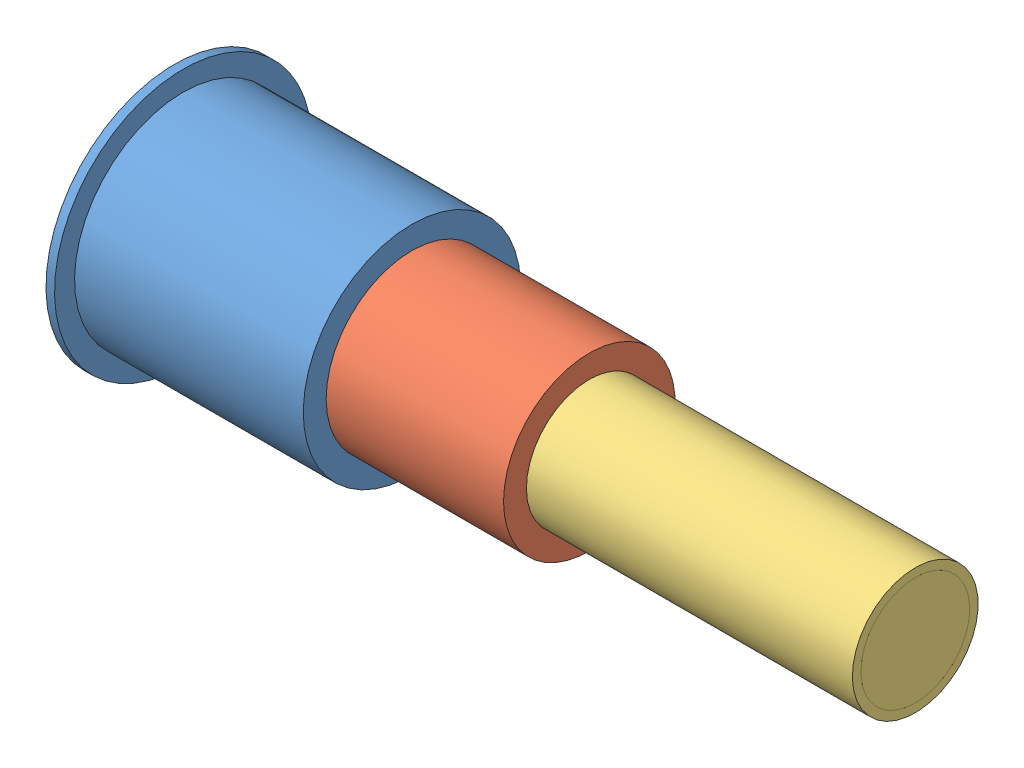
SolidWorks assembly telescope, configuration Default. Lengths in mm.
Overall size (259.04 125.81 125.81).
3 component instances, 3 part files, 5 mates.
Components (placement in the parent):
- Part1^telescope-1: Part1^telescope [Default] at (126.9697 10.5105 -5.8511) x (1 0 0) z (0 0.80601 0.591901) size (83 90 90) (virtual)
- Part2^telescope-1: Part2^telescope [Default] at (100.7918 10.5105 -5.8511) size (83 70 70) (virtual)
- Part3^telescope-1: Part3^telescope [Default] at (-17.9595 10.5105 -5.8511) x (1 0 0) z (0 0.159812 0.987147) size (120 54 54) (virtual)
Mates (geometry in assembly coordinates):
- Concentric1: concentric anti-aligned: cylinder of Part1^telescope-1 through (126.9697 10.5105 -5.8511) axis (1 0 0) radius 38; cylinder of Part2^telescope-1 through (118.7513 10.5105 -5.8511) axis (-1 0 0) radius 30
- Concentric2: concentric anti-aligned: cylinder of Part2^telescope-1 through (118.7513 10.5105 -5.8511) axis (-1 0 0) radius 30; cylinder of Part3^telescope-1 through (194 10.5105 -5.8511) axis (1 0 0) radius 22
- LimitDistance1: limit distance = 62.0405 mm aligned: plane of Part2^telescope-1 through (192.0102 37.5105 -5.8511) normal (1 0 0); plane of Part1^telescope-1 through (129.9697 31.227 -34.0615) normal (1 0 0)
- Concentric3: concentric anti-aligned: cylinder of Part2^telescope-1 through (118.7513 10.5105 -5.8511) axis (-1 0 0) radius 30; cylinder of Part3^telescope-1 through (194 10.5105 -5.8511) axis (1 0 0) radius 22
- LimitDistance4: limit distance = 3 mm aligned: plane of Part2^telescope-1 through (192.0102 37.5105 -5.8511) normal (1 0 0); plane of Part3^telescope-1 through (189.0102 37.1635 -10.1661) normal (1 0 0)
